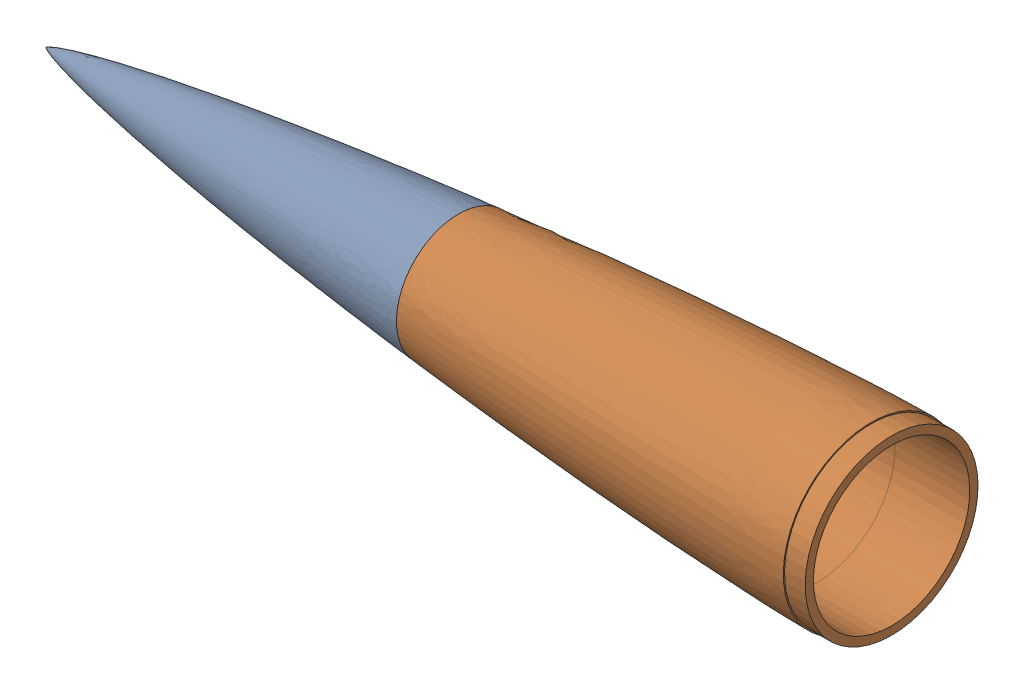
SolidWorks assembly Glassed Nose Cone Asembly, configuration Default. Lengths in mm.
Overall size (410 88.3 88.3).
2 component instances, 2 part files, 1 mates.
Components (placement in the parent):
- Glassed Nose Cone Top-1: Glassed Nose Cone Top [Default] at (1039.7309 884.0805 1243.7924) size (215.02 60.1 60.1)
- Glassed Nosecone Bottom-1: Glassed Nosecone Bottom [Default] at (989.7309 884.0805 1243.7924) x (1 0 0) z (0 -0.999217 0.039559) size (211.44 85 85)
Mates (geometry in assembly coordinates):
- Coincident1: coincident aligned: circle of Glassed Nose Cone Top-1; circle of Glassed Nosecone Bottom-1
